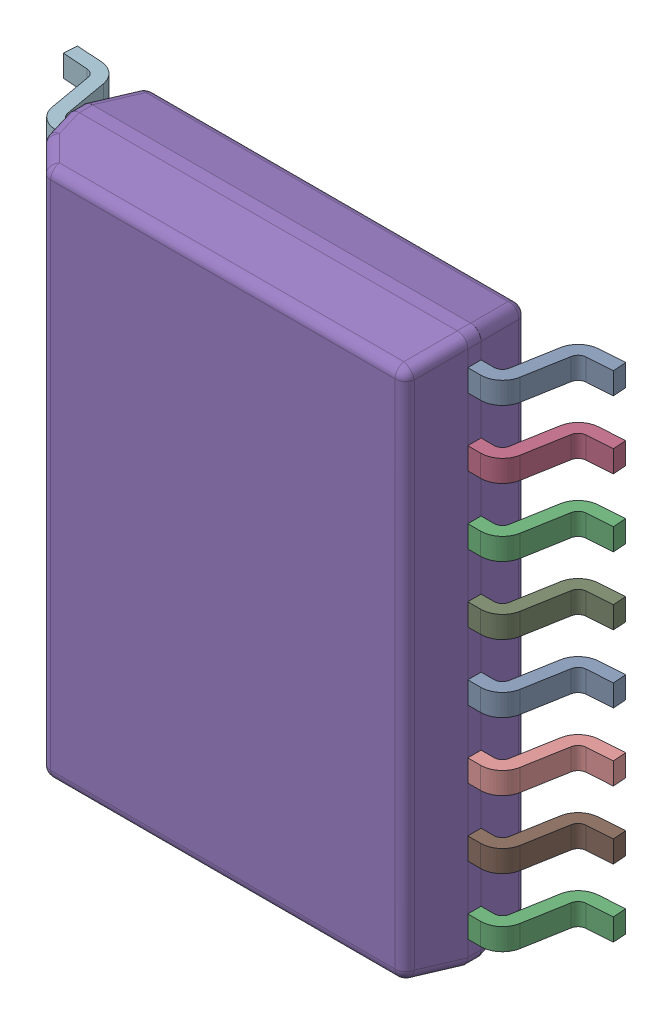
SolidWorks assembly IC1, configuration По умолчанию. Lengths in mm.
Overall size (10.33 10.3 2.59).
18 component instances, 2 part files, 0 mates.
Components (placement in the parent):
- DW0016B_ASM-1: DW0016B_ASM [По умолчанию] at origin size (10.33 10.3 2.59)
  - DW0016B_ASM-Part-1-1: DW0016B_ASM-Part-1 [По умолчанию] at (4.315 -0.635 0.25) x (0 1 0) z (1 0 0) size (0.41 1.57 1.42)
  - DW0016B_ASM-Part-1-2: DW0016B_ASM-Part-1 [По умолчанию] at (-4.315 -1.905 0.25) x (0 -1 0) z (-1 0 0) size (0.41 1.57 1.42)
  - DW0016B_ASM-Part-1-3: DW0016B_ASM-Part-1 [По умолчанию] at (4.315 -4.445 0.25) x (0 1 0) z (1 0 0) size (0.41 1.57 1.42)
  - DW0016B_ASM-Part-1-4: DW0016B_ASM-Part-1 [По умолчанию] at (4.315 3.175 0.25) x (0 1 0) z (1 0 0) size (0.41 1.57 1.42)
  - DW0016B_ASM-Part-1-5: DW0016B_ASM-Part-1 [По умолчанию] at (-4.315 0.635 0.25) x (0 -1 0) z (-1 0 0) size (0.41 1.57 1.42)
  - DW0016B_ASM-Part-1-6: DW0016B_ASM-Part-1 [По умолчанию] at (-4.315 -3.175 0.25) x (0 -1 0) z (-1 0 0) size (0.41 1.57 1.42)
  - DW0016B_ASM-Part-1-7: DW0016B_ASM-Part-1 [По умолчанию] at (-4.315 -4.445 0.25) x (0 -1 0) z (-1 0 0) size (0.41 1.57 1.42)
  - DW0016B_ASM-Part-1-8: DW0016B_ASM-Part-1 [По умолчанию] at (-4.315 3.175 0.25) x (0 -1 0) z (-1 0 0) size (0.41 1.57 1.42)
  - DW0016B_ASM-Part-1-9: DW0016B_ASM-Part-1 [По умолчанию] at (4.315 0.635 0.25) x (0 1 0) z (1 0 0) size (0.41 1.57 1.42)
  - DW0016B_ASM-Part-1-10: DW0016B_ASM-Part-1 [По умолчанию] at (4.315 -1.905 0.25) x (0 1 0) z (1 0 0) size (0.41 1.57 1.42)
  - DW0016B_ASM-Part-1-11: DW0016B_ASM-Part-1 [По умолчанию] at (4.315 -3.175 0.25) x (0 1 0) z (1 0 0) size (0.41 1.57 1.42)
  - DW0016B_ASM-Part-1-12: DW0016B_ASM-Part-1 [По умолчанию] at (-4.315 4.445 0.25) x (0 -1 0) z (-1 0 0) size (0.41 1.57 1.42)
  - DW0016B_ASM-Part-1-13: DW0016B_ASM-Part-1 [По умолчанию] at (4.315 4.445 0.25) x (0 1 0) z (1 0 0) size (0.41 1.57 1.42)
  - DW0016B_ASM-Part-1-14: DW0016B_ASM-Part-1 [По умолчанию] at (-4.315 1.905 0.25) x (0 -1 0) z (-1 0 0) size (0.41 1.57 1.42)
  - DW0016B_ASM-Part-1-15: DW0016B_ASM-Part-1 [По умолчанию] at (4.315 1.905 0.25) x (0 1 0) z (1 0 0) size (0.41 1.57 1.42)
  - DW0016B_ASM-Part-1-16: DW0016B_ASM-Part-1 [По умолчанию] at (-4.315 -0.635 0.25) x (0 -1 0) z (-1 0 0) size (0.41 1.57 1.42)
  - DW0016B_ASM-Part-2-1: DW0016B_ASM-Part-2 [По умолчанию] at (0 0 1.568) x (0 1 0) z (1 0 0) size (10.3 2.29 7.5)
